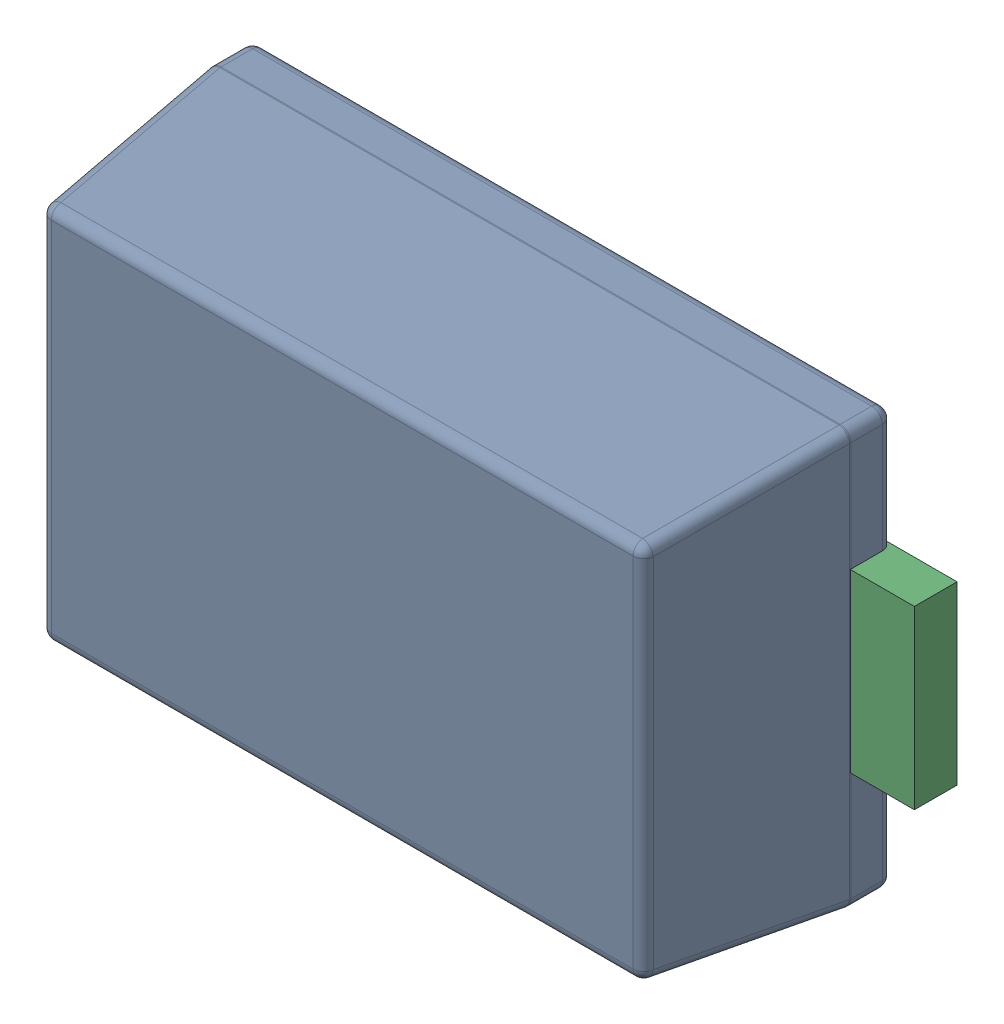
SolidWorks assembly D7, configuration Default. Lengths in mm.
Overall size (3.6 1.96 1.08).
5 component instances, 2 part files, 0 mates.
Components (placement in the parent):
- 809534704-1: 809534704 [Default] at (107.5703 70.231 0) x (1 0 0) z (0 0 1) size (3.6 1.96 1.08)
  - Body_3-1: Body_3 [Default] at (-1.5 -0.975 0) size (3.01 1.96 1.08)
    - Open_CASCADE_STEP_translator_6.8_1.1.1_2-1: Open_CASCADE_STEP_translator_6.8_1.1.1_2 [Default] at origin size (3.01 1.96 1.08)
  - lead_2-1: lead_2 [Default] at (-1.8 -0.4125 0) size (0.68 0.82 0.2)
  - lead_2-2: lead_2 [Default] at (1.8 0.4125 0) x (-1 0 0) z (0 0 1) size (0.68 0.82 0.2)
